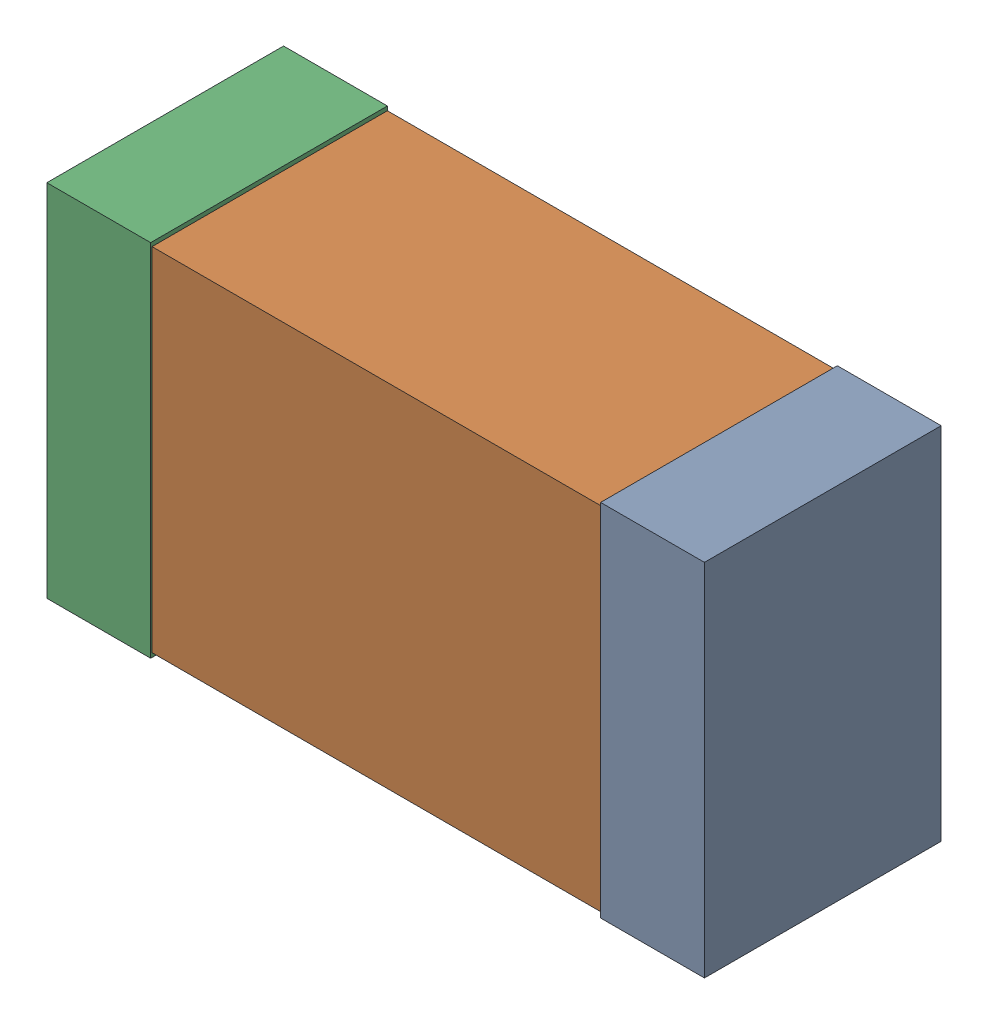
SolidWorks assembly R5Kanaloa_v2.0.0_Motor, configuration Default. Lengths in mm.
Overall size (2.38 1.3 0.85).
6 component instances, 2 part files, 0 mates.
Components (placement in the parent):
- 352877648-1: 352877648 [Default] at (74.347 116.9182 0) size (0.38 1.3 0.85)
  - Extruded_14-1: Extruded_14 [Default] at origin size (0.38 1.3 0.85)
- 352877904-1: 352877904 [Default] at (73.347 116.9182 0) size (2.2 1.27 0.85)
  - Extruded_18-1: Extruded_18 [Default] at origin size (2.2 1.27 0.85)
- 352877648-2: 352877648 [Default] at (72.347 116.9182 0) size (0.38 1.3 0.85)
  - Extruded_14-1: Extruded_14 [Default] at origin size (0.38 1.3 0.85)
